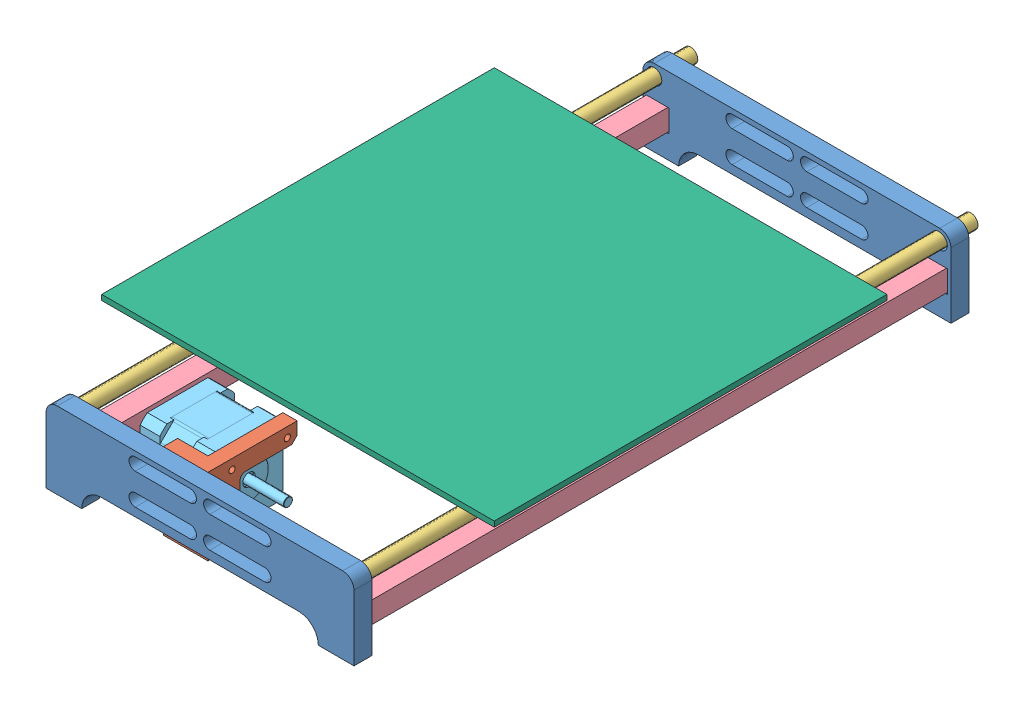
SolidWorks assembly Assem2, configuration Default. Lengths in mm.
Overall size (220 51.5 354.46).
9 component instances, 6 part files, 19 mates.
Components (placement in the parent):
- TopoMotor-1: TopoMotor [Default] at (51.653 82.5734 144.3204) size (172.6 43 10)
- TopoMotor-2: TopoMotor [Default] at (54.0623 82.0734 -179.6796) x (-1 0 0) z (0 0 -1) size (172.6 43 10)
- SuporteNema-1: SuporteNema [Default] at (14.0585 68.8734 144.3204) x (0 1 0) z (-1 0 0) size (43 50 25)
- Y-34-1: Y-34 [Default] at (-26.8924 82.0734 149.861) x (0.917716 0.397236 0) z (-0.397236 0.917716 0) size (8 350 8)
- Tubo-34-1: Tubo-34 [Default] at (-31.1924 58.8734 -187.6796) size (12 12 340)
- Tubo-34-2: Tubo-34 [Default] at (124.9076 58.8734 -187.6796) size (12 12 340)
- Y-34-2: Y-34 [Default] at (132.6076 82.5734 -197.6796) x (0.599115 0.800663 0) z (0.800663 -0.599115 0) size (8 350 8)
- NEMA-17-1: NEMA-17 [Default] at (20.4585 67.8734 115.3204) x (0 0 -1) z (1 0 0) size (54 42 62)
- Y-Vidro-1: Y-Vidro [Default] at (60.152 93.8734 14.446) size (220 3 220)
Mates (geometry in assembly coordinates):
- Distance3: distance = 2 mm aligned: plane of Y-34-2 through (132.6076 82.5734 152.3204) normal (0 0 1); plane of TopoMotor-1 through (-27.3924 82.5734 154.3204) normal (0 0 1)
- Coincident10: coincident anti-aligned: plane of TopoMotor-1 through (-19.1924 71.3734 152.3204) normal (-1 0 0); plane of Tubo-34-1 through (-19.1924 58.8734 152.3204) normal (1 0 0)
- Coincident11: coincident anti-aligned: plane of TopoMotor-1 through (51.653 82.5734 152.3204) normal (0 0 -1); plane of Tubo-34-1 through (-31.1924 58.8734 152.3204) normal (0 0 1)
- Coincident12: coincident anti-aligned: plane of TopoMotor-1 through (-31.6924 58.8734 152.3204) normal (0 1 0); plane of Tubo-34-1 through (-31.1924 58.8734 152.3204) normal (0 -1 0)
- Coincident13: coincident anti-aligned: plane of TopoMotor-1 through (136.9076 71.3734 152.3204) normal (-1 0 0); plane of Tubo-34-2 through (136.9076 58.8734 152.3204) normal (1 0 0)
- Coincident14: coincident anti-aligned: plane of TopoMotor-1 through (51.653 82.5734 152.3204) normal (0 0 -1); plane of Tubo-34-2 through (124.9076 58.8734 152.3204) normal (0 0 1)
- Coincident15: coincident anti-aligned: plane of TopoMotor-1 through (136.9076 58.8734 152.3204) normal (0 1 0); plane of Tubo-34-2 through (124.9076 58.8734 152.3204) normal (0 -1 0)
- Coincident16: coincident: plane of TopoMotor-1 through (-27.3924 82.5734 144.3204) normal (0 0 -1); plane of SuporteNema-1 through (14.0585 68.8734 144.3204) normal (0 0 1)
- Coincident26: coincident: plane of SuporteNema-1 through (39.0585 68.8734 144.3204) normal (-1 0 0); plane of NEMA-17-1 through (39.0585 67.8734 115.3204) normal (-1 0 0)
- Coincident27: coincident: plane of SuporteNema-1 through (23.7723 99.8734 144.3204) normal (0 -1 0); plane of NEMA-17-1 through (13.2955 99.8734 115.3204) normal (0 1 0)
- Coincident28: coincident anti-aligned: plane of TopoMotor-2 through (-31.1924 70.8734 -187.6796) normal (1 0 0); plane of Tubo-34-1 through (-31.1924 58.8734 152.3204) normal (-1 0 0)
- Coincident29: coincident anti-aligned: plane of TopoMotor-2 through (54.0623 82.0734 -187.6796) normal (0 0 1); plane of Tubo-34-1 through (-31.1924 58.8734 -187.6796) normal (0 0 -1)
- Coincident30: coincident anti-aligned: plane of TopoMotor-2 through (-31.1924 70.8734 -187.6796) normal (0 -1 0); plane of Tubo-34-1 through (-31.1924 70.8734 152.3204) normal (0 1 0)
- Concentric8: concentric anti-aligned: circle of TopoMotor-2; cylinder of Y-34-1 through (-26.8924 82.0734 -200.139) axis (0 0 1) radius 4
- Coincident31: coincident: plane of SuporteNema-1 through (14.0585 68.8734 136.3204) normal (0 0 -1); plane of NEMA-17-1 through (20.4585 67.8734 136.3204) normal (0 0 1)
- Coincident33: coincident: plane of TopoMotor-1 through (-27.3924 88.8734 152.3204) normal (0 1 0); plane of SuporteNema-1 through (47.0586 88.8734 94.3204) normal (0 1 0)
- Concentric9: concentric: cylinder of SuporteNema-1 through (47.0585 83.3734 130.8204) axis (-1 0 0) radius 1.75; cylinder of NEMA-17-1 through (39.0585 83.3734 130.8204) axis (-1 0 0) radius 1.621
- Distance6: distance = 20 mm aligned: plane of Y-Vidro-1 through (158.9076 96.8734 -124.2955) normal (1 0 0); plane of TopoMotor-1 through (138.9076 56.8734 152.3204) normal (1 0 0)
- Distance7: distance = 5 mm anti-aligned: plane of Y-Vidro-1 through (60.152 93.8734 14.446) normal (0 -1 0); plane of TopoMotor-1 through (-27.3924 88.8734 152.3204) normal (0 1 0)
